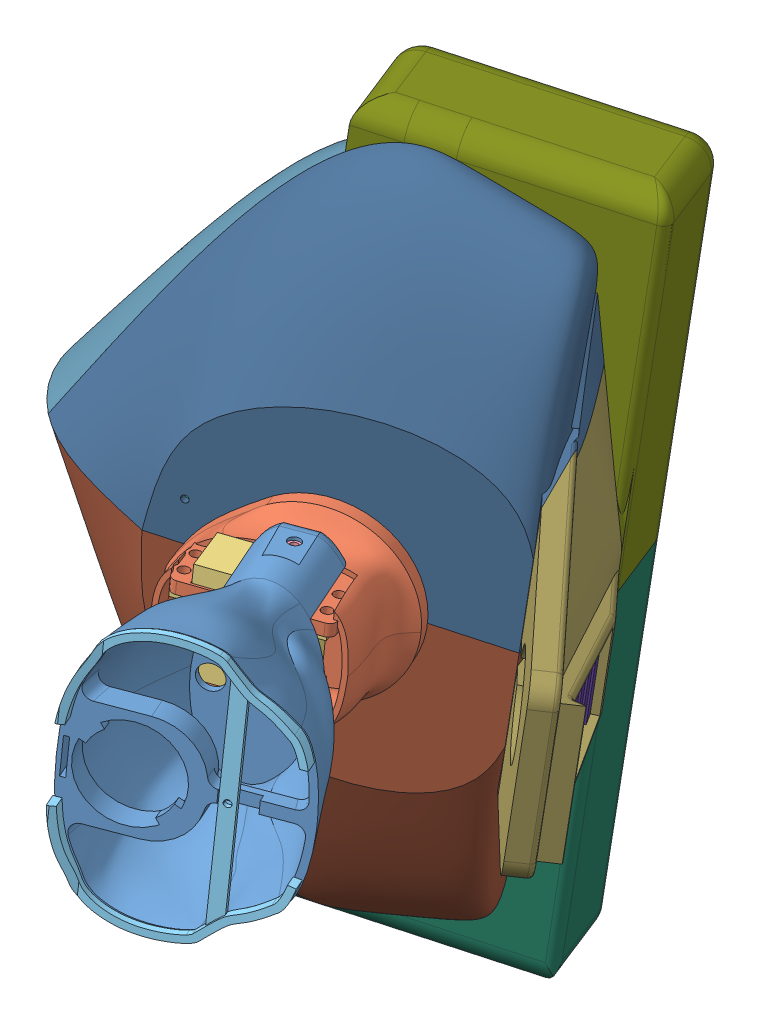
SolidWorks assembly headassm, configuration Default. Lengths in mm.
Overall size (298.24 320.51 300.9).
24 component instances, 19 part files, 6 mates.
Components (placement in the parent):
- neck full assm-1: neck full assm [Default-_flexible1] at (-25.551 -109.2322 285.5515) x (-0.031929 -0.996014 0.083285) z (-0.432591 -0.061347 -0.899501) size (124.6 120.81 194.67) (flexible)
  - Neck assm-1: Neck assm [Default-_flexible1] at origin size (124.17 93.75 129.74) (flexible)
    - mainneck-1: mainneck [Default] at origin size (124.17 91.01 111.8)
    - Neck angle top-1: Neck angle top [Default] at (0 31.4366 121.9799) x (-1 0 0) z (0 0.035984 -0.999352) size (74.22 85.05 43)
    - servo standard-1: servo standard [Default] at (-5.4798 60.8338 92.0183) x (1 0 0) z (0 -0.999352 -0.035984) size (49 20 52)
    - servo horn 1-1: servo horn 1 [Default] at (-35.55 34.5447 76.8381) x (0 0.148416 -0.988925) z (1 0 0) size (38.7 12.89 6.25)
  - neck bottom shim-1: neck bottom shim [Default] at (0.3391 6.0031 0) x (0.999989 0.004745 0) z (0 0 -1) size (124.17 91.01 115.78)
  - neck gearbox assm-1: neck gearbox assm [Default-_flexible1] at (-10.5654 -14.167 125.3411) x (-0.998943 -0.045933 -0.001654) z (0 0.035984 -0.999352) size (44.1 96.66 85) (flexible)
    - neckrot-1: neckrot [Default] at (-12.6434 72.9195 -30) x (0 1 0) z (0 0 1) size (96.66 38 30)
    - neckrot_top-1: neckrot_top [Default] at (-12.6434 72.9195 0) x (0 1 0) z (0 0 1) size (96.66 38 30) (hidden)
    - neckrotlarge-2: neckrotlarge [Default] at (-12.5082 76.0027 -0.2) x (0.891923 0.452187 0) z (0 0 -1) size (32.81 32.81 10)
    - bearing-1: bearing [Default] at (-12.6434 44.9195 -12) x (0.875947 -0.482408 0) z (0 0 -1) size (22 22 7)
    - servo standard-1: servo standard [Default] at (-12.5082 104.3027 -34.0202) x (0 0 -1) z (0 -1 0) size (49 20 52)
    - neckrotlarge mount-1: neckrotlarge mount [Default] at (-12.6434 44.9195 -12) x (0.998943 0.045963 0) z (0 0 1) size (32.81 32.81 17)
- head assm-1: head assm [Default-_flexible1] at (-107.4409 -114.8074 187.4842) x (-0.913572 0.108212 0.392016) z (-0.399888 -0.063637 -0.914352) size (236.3 295.79 192.92) (flexible)
  - bottom back left-1: bottom back left [Default] at (-8.7658 0 43.6041) x (0 -1 0) z (0 0 -1) size (157.97 187.29 45.46)
  - bottom back right-1: bottom back right [Default] at (-8.7658 0 43.6041) x (0 -1 0) z (0 0 -1) size (148.08 181.11 51.5)
  - bottom front-1: bottom front [Default] at (-68.4234 0 -9.4455) x (0 -1 0) z (-0.936784 0 0.34991) size (164.21 114.96 29.45)
  - crown v4-1: crown v4 [Default] at (-8.7658 0 40) x (0 -1 0) z (-1 0 0) size (208.19 39.02 188.74)
  - middle back-1: middle back [Default] at (-8.7658 0 40) x (0 -1 0) z (-1 0 0) size (272.97 45.63 106.33)
  - visor middle front right-1: visor middle front right [Default] at (-8.2725 -147.5 67.2082) x (1 0 0) z (0 1 0) size (109.8 45.62 147.52)
  - visor middle front left-1: visor middle front left [Default] at (-8.2725 147.5 67.2082) x (-1 0 0) z (0 -1 0) size (109.8 45.62 147.52)
  - mouth plate-1: mouth plate [Default] at (-86.0575 -0.1211 -25.0069) x (0 -1 0) z (-0.989195 0 0.146609) size (50.2 57.5 7)
- kinect top-1: kinect top [Default] at (-117.5059 -120.8428 121.6505) x (-0.073997 -0.992089 0.10141) z (0.913572 -0.108212 -0.392016) size (282 37 59)
Mates (geometry in assembly coordinates):
- Coincident4: coincident anti-aligned: plane of head assm-1/visor middle front right-1 through (-139.8432 31.5389 141.047) normal (-0.399888 -0.063637 -0.914352); plane of kinect top-1 through (-97.9781 -18.8215 126.2425) normal (0.399888 0.063637 0.914352)
- Coincident5: coincident anti-aligned: plane of head assm-1/visor middle front right-1 through (-44.2888 20.498 102.7593) normal (-0.913572 0.108212 0.392016); plane of kinect top-1 through (-45.7736 13.8345 101.1383) normal (0.913572 -0.108212 -0.392016)
- Lock1: lock: 
- Coincident12: coincident anti-aligned: plane of neck full assm-1/neck gearbox assm-1/neckrot-1 through (-175.3099 -106.8016 213.3282) normal (0.399888 0.063637 0.914352); plane of ? through (-95.8008 -50.5175 174.638) normal (-0.399888 -0.063637 -0.914352)
- Parallel4: parallel anti-aligned: plane of neck full assm-1/neck gearbox assm-1/neckrot-1 through (-89.9503 -136.2284 178.0446) normal (-0.073997 -0.992089 0.10141); plane of ? through (-120.9029 -149.4555 28.5239) normal (0.073997 0.992089 -0.10141)
- Concentric8: concentric aligned: circle of neck full assm-1/neck gearbox assm-1/neckrot-1; circle of ?
